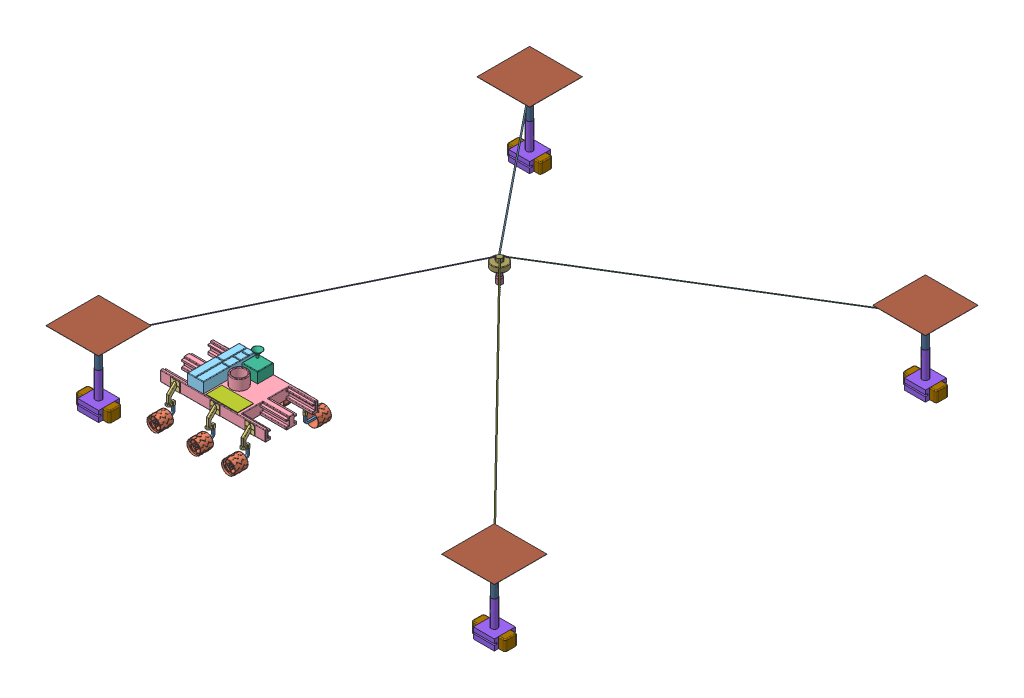
SolidWorks assembly expanced3, configuration Default. Lengths in mm.
Overall size (10022.25 1478.91 10466.05).
78 component instances, 20 part files, 107 mates.
Components (placement in the parent):
- lg-1: lg [Default] at (784.667 1146.0693 1417.0512) size (2000 1016.21 1833.55)
  - act2-1: act2 [Default] at (710 -374.097 990.1927) x (0 1 0) z (1 0 0) size (227.86 360.36 100)
  - Wheel-1: Wheel [Default] at (710 -349.0008 1023.6376) x (0 1 0) z (0 0 -1) size (274.42 270 250)
  - act1-1: act1 [Default] at (710 -171.1455 626.4214) x (-1 0 0) z (0 0 -1) size (180 401.15 176.42)
  - body-1: body [Default] at origin size (2000 400 1000)
  - act1-2: act1 [Default] at (-710 -171.1455 626.4214) x (-1 0 0) z (0 0 -1) size (180 401.15 176.42)
  - Wheel-2: Wheel [Default] at (-710 -349.0008 1023.6376) x (-1 0 0) z (0 0 -1) size (274.42 270 250)
  - act2-2: act2 [Default] at (-710 -374.097 990.1927) x (0 1 0) z (1 0 0) size (227.86 360.36 100)
  - Wheel-3: Wheel [Default] at (-710 -349.0008 -1023.6376) size (274.42 270 250)
  - act2-3: act2 [Default] at (-710 -374.097 -990.1927) x (0 1 0) z (-1 0 0) size (227.86 360.36 100)
  - act1-3: act1 [Default] at (-710 -171.1455 -626.4214) size (180 401.15 176.42)
  - act1-4: act1 [Default] at (710 -171.1455 -626.4214) size (180 401.15 176.42)
  - Wheel-4: Wheel [Default] at (710 -349.0008 -1023.6376) x (0 -1 0) z (0 0 1) size (274.42 270 250)
  - act2-4: act2 [Default] at (710 -374.097 -990.1927) x (0 1 0) z (-1 0 0) size (227.86 360.36 100)
  - tool box-1: tool box [Default] at (-340 200 0) x (0 0 1) z (-1 0 0) size (980 200 300)
  - act1-5: act1 [Default] at (50 -171.1455 626.4214) x (-1 0 0) z (0 0 -1) size (180 401.15 176.42)
  - act2-5: act2 [Default] at (50 -374.097 990.1927) x (0 1 0) z (1 0 0) size (227.86 360.36 100)
  - Wheel-5: Wheel [Default] at (50 -349.0008 1023.6376) x (-1 0 0) z (0 0 -1) size (274.42 270 250)
  - Lab-1: Lab [Default] at (10 200 -340) x (0 0 1) z (-1 0 0) size (324.09 330 324.09)
  - Wheel-6: Wheel [Default] at (50 -349.0008 -1023.6376) size (274.42 270 250)
  - act1-6: act1 [Default] at (50 -171.1455 -626.4214) size (180 401.15 176.42)
  - act2-6: act2 [Default] at (50 -374.097 -990.1927) x (0 1 0) z (-1 0 0) size (227.86 360.36 100)
  - solar panel-1: solar panel [Default] at (150 200 330) size (600 10 300)
- posfasdfale-1: posfasdfale [Default] at (-2888.13 27.5984 -4952.4756) x (0 0 -1) z (1 0 0) size (1000 1398.2 1000)
  - pilon-1: pilon [Default] at (750.6878 634.4701 2074.8363) size (400 700 400)
  - fix-1: fix [Default] at (704.1878 324.4701 2336.3363) size (236 530 123)
    - screw - Copy-1: screw - Copy [Default] at origin size (83 330 83) (hidden)
    - Part3^fix-1: Part3^fix [Default] at origin size (236 200 123) (virtual)
    - screw2 - Copy - Copy-1: screw2 - Copy - Copy [Default] at (97.0846 0 0) size (83 330 83) (hidden)
  - fix-2: fix [Default] at (797.1878 324.4701 1813.3363) x (-1 0 0) z (0 0 -1) size (236 530 123)
    - screw - Copy-1: screw - Copy [Default] at origin size (83 330 83) (hidden)
    - Part3^fix-1: Part3^fix [Default] at origin size (236 200 123) (virtual)
    - screw2 - Copy - Copy-1: screw2 - Copy - Copy [Default] at (97.0846 0 0) size (83 330 83) (hidden)
  - pilon2-1: pilon2 [Default] at (750.6878 1318.6712 2074.8363) x (0.920349 0 0.391098) z (-0.391098 0 0.920349) size (110 500 110)
  - cap-2: cap [Default] at (750.6878 1818.6712 2074.8363) x (0 0 1) z (-1 0 0) size (1000 264 1000)
- Part1^expanced3-2: Part1^expanced3 [Default] at (784.667 1716.0693 1417.0512) x (0.719935 0 0.694042) z (0 1 0) (virtual)
- posfasdfale-2: posfasdfale [Default] at (-2888.13 27.5984 3241.9466) x (0 0 -1) z (1 0 0) size (1000 1398.2 1000)
  - pilon-1: pilon [Default] at (750.6878 634.4701 2074.8363) size (400 700 400)
  - fix-1: fix [Default] at (704.1878 324.4701 2336.3363) size (236 530 123)
    - screw - Copy-1: screw - Copy [Default] at origin size (83 330 83) (hidden)
    - Part3^fix-1: Part3^fix [Default] at origin size (236 200 123) (virtual)
    - screw2 - Copy - Copy-1: screw2 - Copy - Copy [Default] at (97.0846 0 0) size (83 330 83) (hidden)
  - fix-2: fix [Default] at (797.1878 324.4701 1813.3363) x (-1 0 0) z (0 0 -1) size (236 530 123)
    - screw - Copy-1: screw - Copy [Default] at origin size (83 330 83) (hidden)
    - Part3^fix-1: Part3^fix [Default] at origin size (236 200 123) (virtual)
    - screw2 - Copy - Copy-1: screw2 - Copy - Copy [Default] at (97.0846 0 0) size (83 330 83) (hidden)
  - pilon2-1: pilon2 [Default] at (750.6878 1318.6712 2074.8363) x (0.920349 0 0.391098) z (-0.391098 0 0.920349) size (110 500 110)
  - cap-2: cap [Default] at (750.6878 1818.6712 2074.8363) x (0 0 1) z (-1 0 0) size (1000 264 1000)
- posfasdfale-3: posfasdfale [Default] at (4634.957 27.5984 3241.9466) x (0 0 -1) z (1 0 0) size (1000 1398.2 1000)
  - pilon-1: pilon [Default] at (750.6878 634.4701 2074.8363) size (400 700 400)
  - fix-1: fix [Default] at (704.1878 324.4701 2336.3363) size (236 530 123)
    - screw - Copy-1: screw - Copy [Default] at origin size (83 330 83) (hidden)
    - Part3^fix-1: Part3^fix [Default] at origin size (236 200 123) (virtual)
    - screw2 - Copy - Copy-1: screw2 - Copy - Copy [Default] at (97.0846 0 0) size (83 330 83) (hidden)
  - fix-2: fix [Default] at (797.1878 324.4701 1813.3363) x (-1 0 0) z (0 0 -1) size (236 530 123)
    - screw - Copy-1: screw - Copy [Default] at origin size (83 330 83) (hidden)
    - Part3^fix-1: Part3^fix [Default] at origin size (236 200 123) (virtual)
    - screw2 - Copy - Copy-1: screw2 - Copy - Copy [Default] at (97.0846 0 0) size (83 330 83) (hidden)
  - pilon2-1: pilon2 [Default] at (750.6878 1318.6712 2074.8363) x (0.920349 0 0.391098) z (-0.391098 0 0.920349) size (110 500 110)
  - cap-2: cap [Default] at (750.6878 1818.6712 2074.8363) x (0 0 1) z (-1 0 0) size (1000 264 1000)
- posfasdfale-4: posfasdfale [Default] at (4634.957 27.5984 -4952.4756) x (0 0 -1) z (1 0 0) size (1000 1398.2 1000)
  - pilon-1: pilon [Default] at (750.6878 634.4701 2074.8363) size (400 700 400)
  - fix-1: fix [Default] at (704.1878 324.4701 2336.3363) size (236 530 123)
    - screw - Copy-1: screw - Copy [Default] at origin size (83 330 83) (hidden)
    - Part3^fix-1: Part3^fix [Default] at origin size (236 200 123) (virtual)
    - screw2 - Copy - Copy-1: screw2 - Copy - Copy [Default] at (97.0846 0 0) size (83 330 83) (hidden)
  - fix-2: fix [Default] at (797.1878 324.4701 1813.3363) x (-1 0 0) z (0 0 -1) size (236 530 123)
    - screw - Copy-1: screw - Copy [Default] at origin size (83 330 83) (hidden)
    - Part3^fix-1: Part3^fix [Default] at origin size (236 200 123) (virtual)
    - screw2 - Copy - Copy-1: screw2 - Copy - Copy [Default] at (97.0846 0 0) size (83 330 83) (hidden)
  - pilon2-1: pilon2 [Default] at (750.6878 1318.6712 2074.8363) x (0.920349 0 0.391098) z (-0.391098 0 0.920349) size (110 500 110)
  - cap-2: cap [Default] at (750.6878 1818.6712 2074.8363) x (0 0 1) z (-1 0 0) size (1000 264 1000)
- arm-1: arm [Default] at (963.8673 992.0685 -3353.7362) x (0.725374 0 0.688355) z (-0.688355 0 0.725374) size (300 300 300)
- burghiu-1: burghiu [Default] at (963.8673 942.0685 -3353.7362) x (0.999999 0 0.001694) z (0.001694 0 -0.999999) size (111.84 360.71 111.84)
- Part2^expanced3-4: Part2^expanced3 [Default] at (963.8673 1162.0685 -3353.7362) x (0.725374 0 0.688355) z (0 1 0) size (2868.57 503.25 739.2) (virtual)
- Part3^expanced3-1: Part3^expanced3 [Default] at (963.8673 1162.0685 -3353.7362) x (0.725374 0 0.688355) z (0 1 0) size (2568.48 5621.8 739.2) (virtual)
- Part4^expanced3-1: Part4^expanced3 [Default] at (963.8673 1162.0685 -3353.7362) x (0.725374 0 0.688355) z (0 1 0) size (8153.61 306.92 739.2) (virtual)
- Part5^expanced3-1: Part5^expanced3 [Default] at (963.8673 1162.0685 -3353.7362) x (0.725374 0 0.688355) z (0 1 0) size (2756.55 5425.47 739.2) (virtual)
Mates (geometry in assembly coordinates):
- Coincident1: coincident: plane of lg-1/body-1 through (1784.667 1146.0693 1867.0512) normal (0 0 -1); plane of ? through (1807.667 1396.0693 1867.0512) normal (0 0 1)
- Coincident2: coincident: plane of lg-1/body-1 through (1284.667 1346.0693 1917.0512) normal (1 0 0); plane of ? through (1284.667 1396.0693 1589.0512) normal (-1 0 0)
- Coincident3: coincident: plane of lg-1/body-1 through (1784.667 1196.0693 1417.0512) normal (0 1 0); plane of ? through (1607.667 1196.0693 1667.0512) normal (0 -1 0)
- Coincident4: coincident: plane of lg-1/body-1 through (1784.667 1146.0693 967.0512) normal (0 0 1); plane of ? through (1807.667 1396.0693 967.0512) normal (0 0 -1)
- Coincident5: coincident: plane of lg-1/body-1 through (1284.667 1346.0693 1917.0512) normal (1 0 0); plane of ? through (1284.667 1396.0693 1089.0512) normal (-1 0 0)
- Coincident6: coincident: plane of lg-1/body-1 through (1784.667 1196.0693 1417.0512) normal (0 1 0); plane of ? through (1607.667 1196.0693 1167.0512) normal (0 -1 0)
- Coincident7: coincident: plane of lg-1/body-1 through (-215.333 1146.0693 967.0512) normal (0 0 1); plane of ? through (161.667 1396.0693 967.0512) normal (0 0 -1)
- Coincident8: coincident: plane of lg-1/body-1 through (284.667 1346.0693 1917.0512) normal (-1 0 0); plane of ? through (284.667 1396.0693 1245.0512) normal (1 0 0)
- Coincident9: coincident: plane of lg-1/body-1 through (-215.333 1196.0693 1417.0512) normal (0 1 0); plane of ? through (-38.333 1196.0693 1167.0512) normal (0 -1 0)
- Coincident10: coincident: plane of lg-1/body-1 through (-215.333 1146.0693 1867.0512) normal (0 0 -1); plane of ? through (161.667 1396.0693 1867.0512) normal (0 0 1)
- Coincident11: coincident: plane of lg-1/body-1 through (284.667 1346.0693 1917.0512) normal (-1 0 0); plane of ? through (284.667 1396.0693 1745.0512) normal (1 0 0)
- Coincident12: coincident: plane of lg-1/body-1 through (-215.333 1196.0693 1417.0512) normal (0 1 0); plane of ? through (-38.333 1196.0693 1667.0512) normal (0 -1 0)
- InPlace1: in place: plane of ? through (784.667 1716.0693 1417.0512) normal (0 1 0); plane of ? through (0 1716.0693 0) normal (0 1 0); moOrthogonalPlaneRef_w of ? through (784.667 1716.0693 1417.0512) normal (0 1 0); plane of ? through (0 1716.0693 0) normal (0 0 -1); plane of ? through (784.667 1716.0693 1417.0512) normal (0 1 0); plane of ? through (0 1716.0693 0) normal (1 0 0); plane of ? through (784.667 1716.0693 1417.0512) normal (0 1 0); unknown of Part1^expanced3-2
- Coincident13: coincident: plane of assembly through (784.667 1716.0693 1417.0512) normal (0 1 0); plane of ? through (784.667 1716.0693 1417.0512) normal (0 1 0)
- Coincident14: coincident: moOrthogonalPlaneRef_w of ? through (784.667 1716.0693 1417.0512) normal (0.694042 0 -0.719935); plane of Part1^expanced3-2 through (784.667 1716.0693 1417.0512) normal (0.694042 0 -0.719935)
- Coincident15: coincident: moOrthogonalPlaneRef_w of ? through (784.667 1716.0693 1417.0512) normal (-0.719935 0 -0.694042); plane of Part1^expanced3-2 through (784.667 1716.0693 1417.0512) normal (0.719935 0 0.694042)
- InPlace2: in place: plane of ? through (784.667 1716.0693 1417.0512) normal (0 1 0); plane of ? through (0 1716.0693 0) normal (0 1 0); plane of ? through (784.667 1716.0693 1417.0512) normal (0 1 0); plane of ? through (0 1716.0693 0) normal (0 0 -1); plane of ? through (784.667 1716.0693 1417.0512) normal (0 1 0); plane of ? through (0 1716.0693 0) normal (1 0 0); plane of ? through (784.667 1716.0693 1417.0512) normal (0 1 0); unknown of Part1^expanced3-2
- Coincident16: coincident: plane of ?; plane of ?
- Coincident17: coincident: moOrthogonalPlaneRef_w of ? through (784.667 1716.0693 1417.0512) normal (0.694042 0 -0.719935); plane of Part1^expanced3-2 through (784.667 1716.0693 1417.0512) normal (0.694042 0 -0.719935)
- Coincident18: coincident: moOrthogonalPlaneRef_w of ? through (784.667 1716.0693 1417.0512) normal (-0.719935 0 -0.694042); plane of Part1^expanced3-2 through (784.667 1716.0693 1417.0512) normal (0.719935 0 0.694042)
- InPlace3: in place: plane of ? through (784.667 1716.0693 1417.0512) normal (0 1 0); plane of ? through (0 1716.0693 0) normal (0 1 0); plane of ? through (784.667 1716.0693 1417.0512) normal (0 1 0); plane of ? through (0 1716.0693 0) normal (0 0 -1); plane of ? through (784.667 1716.0693 1417.0512) normal (0 1 0); plane of ? through (0 1716.0693 0) normal (1 0 0); plane of ? through (784.667 1716.0693 1417.0512) normal (0 1 0); unknown of Part1^expanced3-2
- Coincident19: coincident: plane of ?; plane of ?
- Coincident20: coincident: moOrthogonalPlaneRef_w of ? through (784.667 1716.0693 1417.0512) normal (0.694042 0 -0.719935); plane of Part1^expanced3-2 through (784.667 1716.0693 1417.0512) normal (0.694042 0 -0.719935)
- Coincident21: coincident: moOrthogonalPlaneRef_w of ? through (784.667 1716.0693 1417.0512) normal (-0.719935 0 -0.694042); plane of Part1^expanced3-2 through (784.667 1716.0693 1417.0512) normal (0.719935 0 0.694042)
- InPlace4: in place: plane of ? through (784.667 1716.0693 1417.0512) normal (0 1 0); plane of ? through (0 1716.0693 0) normal (0 1 0); plane of ? through (784.667 1716.0693 1417.0512) normal (0 1 0); plane of ? through (0 1716.0693 0) normal (0 0 -1); plane of ? through (784.667 1716.0693 1417.0512) normal (0 1 0); plane of ? through (0 1716.0693 0) normal (1 0 0); plane of ? through (784.667 1716.0693 1417.0512) normal (0 1 0); unknown of Part1^expanced3-2
- Coincident22: coincident: plane of ?; plane of ?
- Coincident23: coincident: moOrthogonalPlaneRef_w of ? through (784.667 1716.0693 1417.0512) normal (0.694042 0 -0.719935); plane of Part1^expanced3-2 through (784.667 1716.0693 1417.0512) normal (0.694042 0 -0.719935)
- Coincident24: coincident: moOrthogonalPlaneRef_w of ? through (784.667 1716.0693 1417.0512) normal (-0.719935 0 -0.694042); plane of Part1^expanced3-2 through (784.667 1716.0693 1417.0512) normal (0.719935 0 0.694042)
- InPlace5: in place: plane of ? through (784.667 1716.0693 1417.0512) normal (0 1 0); plane of ? through (0 1716.0693 0) normal (0 1 0); plane of ? through (784.667 1716.0693 1417.0512) normal (0 1 0); plane of ? through (0 1716.0693 0) normal (0 0 -1); plane of ? through (784.667 1716.0693 1417.0512) normal (0 1 0); plane of ? through (0 1716.0693 0) normal (1 0 0); plane of ? through (784.667 1716.0693 1417.0512) normal (0 1 0); unknown of Part1^expanced3-2
- Coincident13: coincident: plane of ?; plane of ?
- Coincident14: coincident: moOrthogonalPlaneRef_w of ? through (784.667 1716.0693 1417.0512) normal (0.694042 0 -0.719935); plane of Part1^expanced3-2 through (784.667 1716.0693 1417.0512) normal (0.694042 0 -0.719935)
- Coincident15: coincident: moOrthogonalPlaneRef_w of ? through (784.667 1716.0693 1417.0512) normal (-0.719935 0 -0.694042); plane of Part1^expanced3-2 through (784.667 1716.0693 1417.0512) normal (0.719935 0 0.694042)
- InPlace6: in place: plane of ? through (784.667 1716.0693 1417.0512) normal (0 1 0); plane of ? through (0 1716.0693 0) normal (0 1 0); plane of ? through (784.667 1716.0693 1417.0512) normal (0 1 0); plane of ? through (0 1716.0693 0) normal (0 0 -1); plane of ? through (784.667 1716.0693 1417.0512) normal (0 1 0); plane of ? through (0 1716.0693 0) normal (1 0 0); plane of ? through (784.667 1716.0693 1417.0512) normal (0 1 0); unknown of Part1^expanced3-2
- Coincident16: coincident: plane of ?; plane of ?
- Coincident17: coincident: moOrthogonalPlaneRef_w of ? through (784.667 1716.0693 1417.0512) normal (0.694042 0 -0.719935); plane of Part1^expanced3-2 through (784.667 1716.0693 1417.0512) normal (0.694042 0 -0.719935)
- Coincident18: coincident: moOrthogonalPlaneRef_w of ? through (784.667 1716.0693 1417.0512) normal (-0.719935 0 -0.694042); plane of Part1^expanced3-2 through (784.667 1716.0693 1417.0512) normal (0.719935 0 0.694042)
- InPlace7: in place: plane of ? through (784.667 1716.0693 1417.0512) normal (0 1 0); plane of ? through (0 1716.0693 0) normal (0 1 0); plane of ? through (784.667 1716.0693 1417.0512) normal (0 1 0); plane of ? through (0 1716.0693 0) normal (0 0 -1); plane of ? through (784.667 1716.0693 1417.0512) normal (0 1 0); plane of ? through (0 1716.0693 0) normal (1 0 0); plane of ? through (784.667 1716.0693 1417.0512) normal (0 1 0); unknown of Part1^expanced3-2
- Coincident19: coincident: plane of ?; plane of ?
- Coincident20: coincident: moOrthogonalPlaneRef_w of ? through (784.667 1716.0693 1417.0512) normal (0.694042 0 -0.719935); plane of Part1^expanced3-2 through (784.667 1716.0693 1417.0512) normal (0.694042 0 -0.719935)
- Coincident21: coincident: moOrthogonalPlaneRef_w of ? through (784.667 1716.0693 1417.0512) normal (-0.719935 0 -0.694042); plane of Part1^expanced3-2 through (784.667 1716.0693 1417.0512) normal (0.719935 0 0.694042)
- Coincident13: coincident: plane of lg-1/body-1 through (1784.667 1146.0693 1467.0512) normal (0 0 1); plane of ? through (1807.667 1396.0693 1467.0512) normal (0 0 -1)
- Coincident14: coincident: plane of lg-1/body-1 through (1284.667 1346.0693 1917.0512) normal (1 0 0); plane of ? through (1284.667 1396.0693 1589.0512) normal (-1 0 0)
- Coincident17: coincident: plane of lg-1/body-1 through (1784.667 1146.0693 1367.0512) normal (0 0 -1); plane of ? through (1807.667 1396.0693 1367.0512) normal (0 0 1)
- Coincident18: coincident: plane of lg-1/body-1 through (1284.667 1346.0693 1917.0512) normal (1 0 0); plane of ? through (1284.667 1396.0693 1089.0512) normal (-1 0 0)
- Coincident19: coincident: plane of lg-1/body-1 through (-215.333 1146.0693 1817.0512) normal (0 0 -1); plane of ? through (161.667 1346.0693 1817.0512) normal (0 0 1)
- Coincident20: coincident: plane of lg-1/body-1 through (284.667 1346.0693 1917.0512) normal (-1 0 0); plane of ? through (284.667 1346.0693 1695.0512) normal (1 0 0)
- Coincident21: coincident: plane of lg-1/body-1 through (784.667 1146.0693 1417.0512) normal (0 -1 0); plane of ? through (-38.333 1146.0693 1617.0512) normal (0 -1 0)
- InPlace8: in place: plane of ? through (784.667 1716.0693 1417.0512) normal (0 1 0); plane of ? through (0 1716.0693 0) normal (0 1 0); plane of ? through (784.667 1716.0693 1417.0512) normal (0 1 0); plane of ? through (0 1716.0693 0) normal (0 0 -1); plane of ? through (784.667 1716.0693 1417.0512) normal (0 1 0); plane of ? through (0 1716.0693 0) normal (1 0 0); plane of ? through (784.667 1716.0693 1417.0512) normal (0 1 0); unknown of Part1^expanced3-2
- Coincident22: coincident: plane of ?; plane of Part1^expanced3-2
- Coincident23: coincident: moOrthogonalPlaneRef_w of ? through (784.667 1716.0693 1417.0512) normal (0.694042 0 -0.719935); plane of Part1^expanced3-2 through (784.667 1716.0693 1417.0512) normal (0.694042 0 -0.719935)
- Coincident24: coincident: moOrthogonalPlaneRef_w of ? through (784.667 1716.0693 1417.0512) normal (-0.719935 0 -0.694042); plane of Part1^expanced3-2 through (784.667 1716.0693 1417.0512) normal (0.719935 0 0.694042)
- InPlace9: in place: plane of ? through (784.667 1716.0693 1417.0512) normal (0 1 0); plane of ? through (0 1716.0693 0) normal (0 1 0); plane of ? through (784.667 1716.0693 1417.0512) normal (0 1 0); plane of ? through (0 1716.0693 0) normal (0 0 -1); plane of ? through (784.667 1716.0693 1417.0512) normal (0 1 0); plane of ? through (0 1716.0693 0) normal (1 0 0); plane of ? through (784.667 1716.0693 1417.0512) normal (0 1 0); unknown of Part1^expanced3-2
- Coincident25: coincident: plane of ?; plane of ?
- Coincident26: coincident: moOrthogonalPlaneRef_w of ? through (784.667 1716.0693 1417.0512) normal (0.694042 0 -0.719935); plane of Part1^expanced3-2 through (784.667 1716.0693 1417.0512) normal (0.694042 0 -0.719935)
- Coincident27: coincident: moOrthogonalPlaneRef_w of ? through (784.667 1716.0693 1417.0512) normal (-0.719935 0 -0.694042); plane of Part1^expanced3-2 through (784.667 1716.0693 1417.0512) normal (0.719935 0 0.694042)
- InPlace10: in place: plane of ? through (784.667 1716.0693 1417.0512) normal (0 1 0); plane of ? through (0 1716.0693 0) normal (0 1 0); plane of ? through (784.667 1716.0693 1417.0512) normal (0 1 0); plane of ? through (0 1716.0693 0) normal (0 0 -1); plane of ? through (784.667 1716.0693 1417.0512) normal (0 1 0); plane of ? through (0 1716.0693 0) normal (1 0 0); plane of ? through (784.667 1716.0693 1417.0512) normal (0 1 0); unknown of Part1^expanced3-2
- Coincident28: coincident: plane of ?; plane of ?
- Coincident29: coincident: moOrthogonalPlaneRef_w of ? through (784.667 1716.0693 1417.0512) normal (0.694042 0 -0.719935); plane of Part1^expanced3-2 through (784.667 1716.0693 1417.0512) normal (0.694042 0 -0.719935)
- Coincident30: coincident: moOrthogonalPlaneRef_w of ? through (784.667 1716.0693 1417.0512) normal (-0.719935 0 -0.694042); plane of Part1^expanced3-2 through (784.667 1716.0693 1417.0512) normal (0.719935 0 0.694042)
- InPlace11: in place: plane of ? through (784.667 1716.0693 1417.0512) normal (0 1 0); plane of ? through (0 1716.0693 0) normal (0 1 0); plane of ? through (784.667 1716.0693 1417.0512) normal (0 1 0); plane of ? through (0 1716.0693 0) normal (0 0 -1); plane of ? through (784.667 1716.0693 1417.0512) normal (0 1 0); plane of ? through (0 1716.0693 0) normal (1 0 0); plane of ? through (784.667 1716.0693 1417.0512) normal (0 1 0); unknown of Part1^expanced3-2
- Coincident31: coincident: plane of ?; plane of ?
- Coincident32: coincident: moOrthogonalPlaneRef_w of ? through (784.667 1716.0693 1417.0512) normal (0.694042 0 -0.719935); plane of Part1^expanced3-2 through (784.667 1716.0693 1417.0512) normal (0.694042 0 -0.719935)
- Coincident33: coincident: moOrthogonalPlaneRef_w of ? through (784.667 1716.0693 1417.0512) normal (-0.719935 0 -0.694042); plane of Part1^expanced3-2 through (784.667 1716.0693 1417.0512) normal (0.719935 0 0.694042)
- InPlace12: in place: plane of ? through (784.667 1716.0693 1417.0512) normal (0 1 0); plane of ? through (0 1716.0693 0) normal (0 1 0); plane of ? through (784.667 1716.0693 1417.0512) normal (0 1 0); plane of ? through (0 1716.0693 0) normal (0 0 -1); plane of ? through (784.667 1716.0693 1417.0512) normal (0 1 0); plane of ? through (0 1716.0693 0) normal (1 0 0); plane of ? through (784.667 1716.0693 1417.0512) normal (0 1 0); unknown of Part1^expanced3-2
- Coincident34: coincident: plane of ?; plane of Part5^expanced3-1
- Coincident35: coincident: moOrthogonalPlaneRef_w of ? through (784.667 1716.0693 1417.0512) normal (0.694042 0 -0.719935); plane of Part1^expanced3-2
- Coincident36: coincident: moOrthogonalPlaneRef_w of ? through (784.667 1716.0693 1417.0512) normal (-0.719935 0 -0.694042); plane of Part1^expanced3-2
- Coincident26: coincident: plane of lg-1/body-1 through (-215.333 1146.0693 1467.0512) normal (0 0 1); plane of ? through (161.667 1396.0693 1467.0512) normal (0 0 -1)
- Coincident27: coincident: plane of lg-1/body-1 through (284.667 1346.0693 1917.0512) normal (-1 0 0); plane of ? through (284.667 1396.0693 1745.0512) normal (1 0 0)
- Coincident29: coincident: plane of lg-1/body-1 through (-215.333 1196.0693 1417.0512) normal (0 1 0); plane of ? through (-38.333 1196.0693 1667.0512) normal (0 -1 0)
- Coincident30: coincident: plane of lg-1/body-1 through (1784.667 1196.0693 1417.0512) normal (0 1 0); plane of ? through (1607.667 1196.0693 1667.0512) normal (0 -1 0)
- Coincident32: coincident: plane of lg-1/body-1 through (1784.667 1196.0693 1417.0512) normal (0 1 0); plane of ? through (1607.667 1196.0693 1167.0512) normal (0 -1 0)
- Coincident33: coincident: plane of lg-1/Wheel-3 through (74.667 662.0685 500.2745) normal (0 -1 0); plane of posfasdfale-1/pilon-1 through (-813.2937 662.0685 -5703.1633) normal (0 -1 0)
- Distance1: distance = 0 mm: plane of ? through (-1136.2937 862.0685 -5781.1633) normal (-1 0 0); plane of ? through (-1136.2937 862.0685 2413.2588) normal (-1 0 0)
- Distance2: distance = 0 mm: plane of posfasdfale-1/pilon-1 through (-813.2937 662.0685 -5703.1633) normal (0 -1 0); plane of posfasdfale-2/pilon-1 through (-813.2937 662.0685 2491.2588) normal (0 -1 0)
- Distance3: distance = 0 mm: plane of posfasdfale-3/pilon-1 through (6909.7933 862.0685 2691.2588) normal (0 0 1); plane of posfasdfale-2/pilon-1 through (-613.2937 862.0685 2691.2588) normal (0 0 1)
- Distance4: distance = 0 mm: plane of posfasdfale-2/pilon-1 through (-813.2937 662.0685 2491.2588) normal (0 -1 0); plane of posfasdfale-3/pilon-1 through (6709.7933 662.0685 2491.2588) normal (0 -1 0)
- Distance5: distance = 0 mm: plane of posfasdfale-1/pilon-1 through (-613.2937 862.0685 -5903.1633) normal (0 0 -1); plane of posfasdfale-4/pilon-1 through (6909.7933 862.0685 -5903.1633) normal (0 0 -1)
- Distance6: distance = 0 mm: plane of posfasdfale-4/pilon-1 through (6709.7933 662.0685 -5703.1633) normal (0 -1 0); plane of posfasdfale-1/pilon-1 through (-813.2937 662.0685 -5703.1633) normal (0 -1 0)
- Distance7: distance = 0 mm: plane of ? through (7032.7933 862.0685 -5625.1633) normal (1 0 0); plane of ? through (7032.7933 862.0685 2569.2588) normal (1 0 0)
- Distance8: distance = 0 mm: plane of arm-1 through (963.8673 862.0685 -3353.7362) normal (0 -1 0); plane of posfasdfale-1/pilon-1 through (-813.2937 862.0685 -5703.1633) normal (0 1 0)
- Concentric1: concentric: circle of arm-1; circle of burghiu-1
- Coincident34: coincident: plane of arm-1 through (963.8673 942.0685 -3353.7362) normal (0 -1 0); plane of burghiu-1 through (963.8673 942.0685 -3353.7362) normal (0 1 0)
- InPlace13: in place: plane of ? through (963.8673 1162.0685 -3545.9569) normal (0 1 0); plane of ? through (0 1162.0685 0) normal (0 1 0); plane of ? through (963.8673 1162.0685 -3545.9569) normal (0 1 0); plane of ? through (0 1162.0685 0) normal (0 0 -1); plane of ? through (963.8673 1162.0685 -3545.9569) normal (0 1 0); plane of ? through (0 1162.0685 0) normal (1 0 0); plane of arm-1 through (963.8673 1162.0685 -3353.7362) normal (0 1 0); unknown of ?
- Coincident35: coincident: plane of arm-1; plane of Part2^expanced3-4
- Coincident36: coincident: moOrthogonalPlaneRef_w of arm-1; plane of Part2^expanced3-4 through (963.8673 1162.0685 -3353.7362) normal (0.688355 0 -0.725374)
- Coincident37: coincident: moOrthogonalPlaneRef_w of arm-1; plane of Part2^expanced3-4 through (963.8673 1162.0685 -3353.7362) normal (0.725374 0 0.688355)
- InPlace14: in place: plane of arm-1 through (963.8673 1162.0685 -3353.7362) normal (0 1 0); plane of ? through (0 1162.0685 0) normal (0 1 0); plane of arm-1 through (963.8673 1162.0685 -3353.7362) normal (0 1 0); plane of ? through (0 1162.0685 0) normal (0 0 -1); plane of arm-1 through (963.8673 1162.0685 -3353.7362) normal (0 1 0); plane of ? through (0 1162.0685 0) normal (1 0 0); plane of arm-1 through (963.8673 1162.0685 -3353.7362) normal (0 1 0); unknown of ?
- Coincident38: coincident: plane of arm-1; plane of ?
- Coincident39: coincident: moOrthogonalPlaneRef_w of arm-1 through (963.8673 1162.0685 -3353.7362) normal (0.688355 0 -0.725374); plane of ? through (963.8673 1162.0685 -3353.7362) normal (0.688355 0 -0.725374)
- Coincident40: coincident: moOrthogonalPlaneRef_w of arm-1 through (963.8673 1162.0685 -3353.7362) normal (-0.725374 0 -0.688355); plane of ? through (963.8673 1162.0685 -3353.7362) normal (0.725374 0 0.688355)
- InPlace15: in place: plane of arm-1 through (963.8673 1162.0685 -3353.7362) normal (0 1 0); plane of ? through (0 1162.0685 0) normal (0 1 0); plane of arm-1 through (963.8673 1162.0685 -3353.7362) normal (0 1 0); plane of ? through (0 1162.0685 0) normal (0 0 -1); plane of arm-1 through (963.8673 1162.0685 -3353.7362) normal (0 1 0); plane of ? through (0 1162.0685 0) normal (1 0 0); plane of arm-1 through (963.8673 1162.0685 -3353.7362) normal (0 1 0); unknown of ?
- Coincident41: coincident: plane of arm-1; plane of ?
- Coincident42: coincident: moOrthogonalPlaneRef_w of arm-1 through (963.8673 1162.0685 -3353.7362) normal (0.688355 0 -0.725374); plane of ? through (963.8673 1162.0685 -3353.7362) normal (0.688355 0 -0.725374)
- Coincident43: coincident: moOrthogonalPlaneRef_w of arm-1 through (963.8673 1162.0685 -3353.7362) normal (-0.725374 0 -0.688355); plane of ? through (963.8673 1162.0685 -3353.7362) normal (0.725374 0 0.688355)
- InPlace16: in place: plane of arm-1 through (963.8673 1162.0685 -3353.7362) normal (0 1 0); plane of ? through (0 1162.0685 0) normal (0 1 0); plane of arm-1 through (963.8673 1162.0685 -3353.7362) normal (0 1 0); plane of ? through (0 1162.0685 0) normal (0 0 -1); plane of arm-1 through (963.8673 1162.0685 -3353.7362) normal (0 1 0); plane of ? through (0 1162.0685 0) normal (1 0 0); plane of arm-1 through (963.8673 1162.0685 -3353.7362) normal (0 1 0); unknown of ?
- Coincident35: coincident: plane of arm-1; plane of Part3^expanced3-1
- Coincident36: coincident: moOrthogonalPlaneRef_w of arm-1 through (963.8673 1162.0685 -3353.7362) normal (0.688355 0 -0.725374); plane of Part3^expanced3-1 through (963.8673 1162.0685 -3353.7362) normal (0.688355 0 -0.725374)
- Coincident37: coincident: moOrthogonalPlaneRef_w of arm-1 through (963.8673 1162.0685 -3353.7362) normal (-0.725374 0 -0.688355); plane of Part3^expanced3-1 through (963.8673 1162.0685 -3353.7362) normal (0.725374 0 0.688355)
- InPlace17: in place: plane of arm-1 through (963.8673 1162.0685 -3353.7362) normal (0 1 0); plane of ? through (0 1162.0685 0) normal (0 1 0); plane of arm-1 through (963.8673 1162.0685 -3353.7362) normal (0 1 0); plane of ? through (0 1162.0685 0) normal (0 0 -1); plane of arm-1 through (963.8673 1162.0685 -3353.7362) normal (0 1 0); plane of ? through (0 1162.0685 0) normal (1 0 0); plane of arm-1 through (963.8673 1162.0685 -3353.7362) normal (0 1 0); unknown of ?
- Coincident38: coincident: plane of arm-1; plane of Part4^expanced3-1
- Coincident39: coincident: moOrthogonalPlaneRef_w of arm-1 through (963.8673 1162.0685 -3353.7362) normal (0.688355 0 -0.725374); plane of Part4^expanced3-1 through (963.8673 1162.0685 -3353.7362) normal (0.688355 0 -0.725374)
- Coincident40: coincident: moOrthogonalPlaneRef_w of arm-1 through (963.8673 1162.0685 -3353.7362) normal (-0.725374 0 -0.688355); plane of Part4^expanced3-1 through (963.8673 1162.0685 -3353.7362) normal (0.725374 0 0.688355)
- InPlace18: in place: plane of arm-1 through (963.8673 1162.0685 -3353.7362) normal (0 1 0); plane of ? through (0 1162.0685 0) normal (0 1 0); plane of arm-1 through (963.8673 1162.0685 -3353.7362) normal (0 1 0); plane of ? through (0 1162.0685 0) normal (0 0 -1); plane of arm-1 through (963.8673 1162.0685 -3353.7362) normal (0 1 0); plane of ? through (0 1162.0685 0) normal (1 0 0); plane of arm-1 through (963.8673 1162.0685 -3353.7362) normal (0 1 0); unknown of ?
- Coincident41: coincident: plane of arm-1; plane of Part5^expanced3-1
- Coincident42: coincident: moOrthogonalPlaneRef_w of arm-1 through (963.8673 1162.0685 -3353.7362) normal (0.688355 0 -0.725374); plane of Part5^expanced3-1 through (963.8673 1162.0685 -3353.7362) normal (0.688355 0 -0.725374)
- Coincident43: coincident: moOrthogonalPlaneRef_w of arm-1 through (963.8673 1162.0685 -3353.7362) normal (-0.725374 0 -0.688355); plane of Part5^expanced3-1 through (963.8673 1162.0685 -3353.7362) normal (0.725374 0 0.688355)
